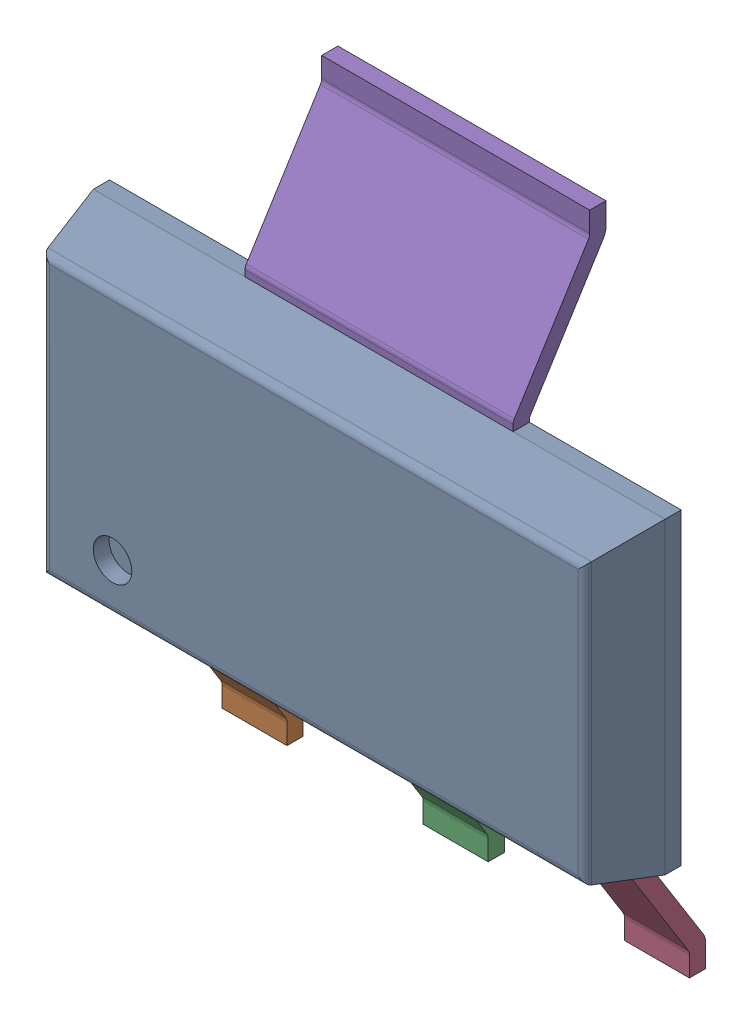
SolidWorks assembly IC10_1.step, configuration Default. Lengths in mm.
Overall size (6.51 7 1.8).
4 component instances, 3 part files, 0 mates.
Components (placement in the parent):
- 6348795088_1.step-3: 6348795088_1.step [Default] at (448.934 292.118 0) x (0 1 0) z (0 0 1) size (7 6.51 1.8)
  - Body-18_1.step-3: Body-18_1.step [Default] at origin size (3.5 6.51 1.06)
  - PinsArrayL_1.step-3: PinsArrayL_1.step [Default] at origin size (1.75 5.32 1.06)
  - FilletPinR_1.step-3: FilletPinR_1.step [Default] at origin size (1.75 3.05 1.06)
